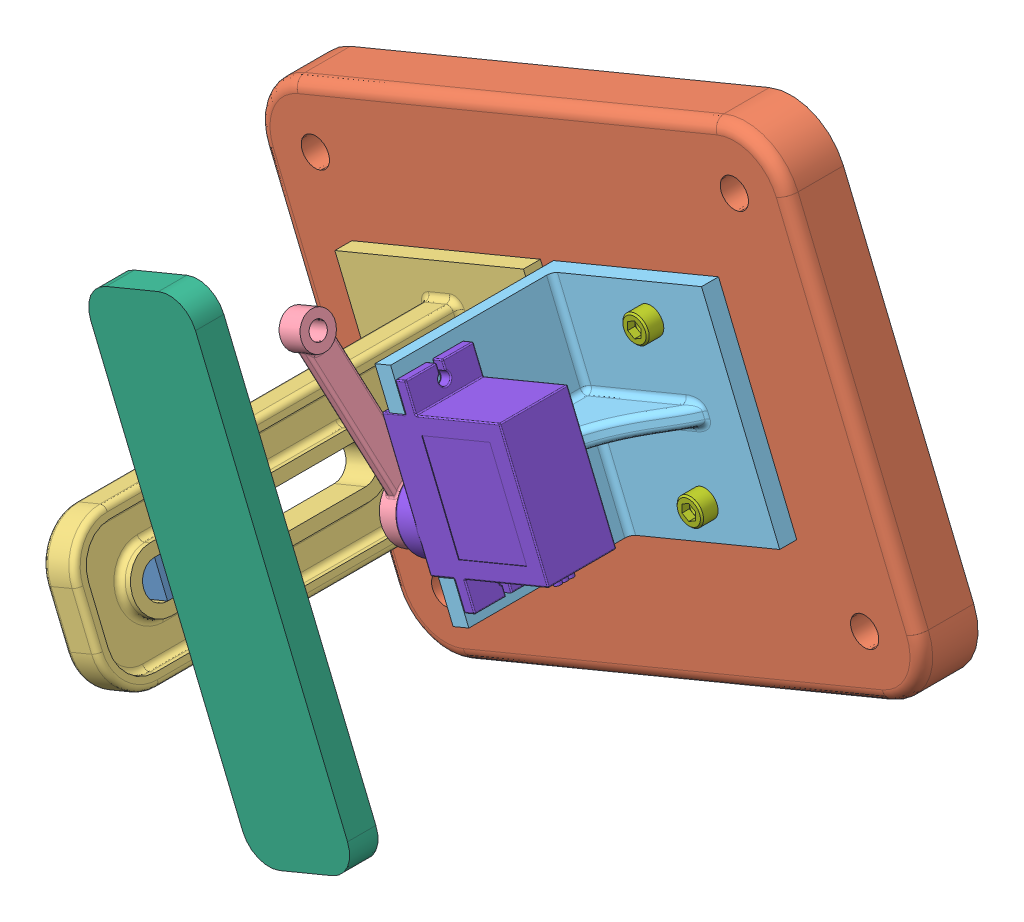
SolidWorks assembly Motion Study Assembly, configuration Default. Lengths in mm.
Overall size (123.02 112.2 83).
12 component instances, 8 part files, 33 mates.
Components (placement in the parent):
- Motion Study Clip-1: Motion Study Clip [Default] at (-120.8204 31.4961 70.2024) x (-0.383049 0.923728 0) z (0.923728 0.383049 0) size (10 7 8)
- Motion Study Base-1: Motion Study Base [Default] at (-97.7272 41.0724 3.7603) x (0.923728 0.383049 0) z (0 0 1) size (100 80 10)
- Motion Study Bracket-1: Motion Study Bracket [Default] at (-116.2018 33.4114 16.7603) x (-0.923728 -0.383049 0) z (0 0 -1) size (36 36 73)
- Motion Study Servo Arm-1: Motion Study Servo Arm [Default] at (-107.6727 46.7817 43.6818) x (0.36603 -0.882686 -0.294768) z (-0.923728 -0.383049 0) size (38 10 4)
- Motion Study Servo Mount-1: Motion Study Servo Mount [Default] at (-95.8797 41.8385 15.2603) x (0.923728 0.383049 0) z (0.383049 -0.923728 0) size (31.5 31.5 36)
- Motion Study Shelf-1: Motion Study Shelf [Default] at (-104.1933 38.391 72.7024) x (-0.383049 0.923728 0) z (0 0 -1) size (80 26 5)
- socket head cap screw_ai-13: socket head cap screw_ai [HX-SHCS 0.112-40x0.125x0.125-N] at (-84.0408 60.2799 19.6051) x (0 0 -1) z (1 0 0) size (6.02 4.65 4.65)
- socket head cap screw_ai-14: socket head cap screw_ai [HX-SHCS 0.112-40x0.125x0.125-N] at (-74.4645 37.1867 19.6051) x (0 0 -1) z (1 0 0) size (6.02 4.65 4.65)
- socket head cap screw_ai-15: socket head cap screw_ai [HX-SHCS 0.112-40x0.125x0.125-N] at (-106.9645 37.2419 19.6051) x (0 0 -1) z (1 0 0) size (6.02 4.65 4.65)
- socket head cap screw_ai-16: socket head cap screw_ai [HX-SHCS 0.112-40x0.125x0.125-N] at (-125.439 29.5809 19.6051) x (0 0 -1) z (1 0 0) size (6.02 4.65 4.65)
- socket head cap screw_ai-17: socket head cap screw_ai [HX-SHCS 0.112-40x0.125x0.125-N] at (-123.4482 30.4064 70.2024) x (0.923728 0.383049 0) z (0 0 1) size (6.02 4.65 4.65)
- Micro Servo SG92R 180-1: Micro Servo SG92R 180 [Valor predeterminado] at (-92.6467 43.1791 39.2603) x (-0.383049 0.923728 0) z (0 0 1) size (32 29 12)
Mates (geometry in assembly coordinates):
- Coincident9: coincident anti-aligned: plane of Motion Study Base-1 through (-97.7272 41.0724 13.7603) normal (0 0 1); plane of Motion Study Bracket-1 through (-116.2018 33.4114 13.7603) normal (0 0 -1)
- Concentric7: concentric aligned: cylinder of Motion Study Base-1 through (-106.9645 37.2419 3.7603) axis (0 0 1) radius 1.5; cylinder of Motion Study Bracket-1 through (-106.9645 37.2419 13.7603) axis (0 0 1) radius 1.5
- Concentric8: concentric aligned: cylinder of Motion Study Base-1 through (-125.439 29.5809 3.7603) axis (0 0 1) radius 1.5; cylinder of Motion Study Bracket-1 through (-125.439 29.5809 13.7603) axis (0 0 1) radius 1.5
- Coincident10: coincident anti-aligned: plane of Motion Study Base-1 through (-97.7272 41.0724 13.7603) normal (0 0 1); plane of Motion Study Servo Mount-1 through (-88.9849 25.2114 13.7603) normal (0 0 -1)
- Concentric10: concentric aligned: cylinder of Motion Study Base-1 through (-84.0408 60.2799 3.7603) axis (0 0 1) radius 1.5; cylinder of Motion Study Servo Mount-1 through (-84.0408 60.2799 6.7603) axis (0 0 1) radius 1.5
- Concentric11: concentric aligned: cylinder of Motion Study Base-1 through (-74.4645 37.1867 3.7603) axis (0 0 1) radius 1.5; cylinder of Motion Study Servo Mount-1 through (-74.4645 37.1867 6.7603) axis (0 0 1) radius 1.5
- Coincident11: coincident anti-aligned: plane of Motion Study Clip-1 through (-118.9729 32.2622 56.3994) normal (0.923728 0.383049 0); plane of Motion Study Bracket-1 through (-114.1848 20.7156 86.7603) normal (-0.923728 -0.383049 0)
- Coincident12: coincident anti-aligned: plane of Motion Study Clip-1 through (-112.2814 31.7893 58.8994) normal (0.383049 -0.923728 0); plane of Motion Study Bracket-1 through (-53.1628 56.3045 73.7603) normal (-0.383049 0.923728 0)
- Coincident14: coincident anti-aligned: plane of Motion Study Clip-1 through (-118.9729 32.2622 56.3994) normal (0.923728 0.383049 0); plane of Motion Study Shelf-1 through (-118.9729 32.2622 58.8994) normal (-0.923728 -0.383049 0)
- Concentric13: concentric aligned: cylinder of Motion Study Clip-1 through (-118.9729 32.2622 56.3994) axis (-0.923728 -0.383049 0) radius 1.425; cylinder of Motion Study Shelf-1 through (-115.278 33.7944 56.3994) axis (-0.923728 -0.383049 0) radius 2
- Coincident16: coincident anti-aligned: plane of Motion Study Clip-1 through (-114.5797 37.3317 53.8994) normal (0 0 1); plane of Motion Study Shelf-1 through (-104.1933 38.391 53.8994) normal (0 0 -1)
- Concentric14: concentric aligned: cylinder of Motion Study Servo Mount-1 through (-84.0408 60.2799 6.7603) axis (0 0 1) radius 1.5; cylinder of socket head cap screw_ai-13 through (-84.0408 60.2799 51.3551) axis (0 0 1) radius 2.3241
- Coincident17: coincident anti-aligned: plane of Motion Study Servo Mount-1 through (-88.9849 25.2114 16.7603) normal (0 0 1); plane of socket head cap screw_ai-13 through (-84.0408 62.604 16.7603) normal (0 0 -1)
- Concentric15: concentric aligned: cylinder of Motion Study Servo Mount-1 through (-74.4645 37.1867 6.7603) axis (0 0 1) radius 1.5; cylinder of socket head cap screw_ai-14 through (-74.4645 37.1867 51.3551) axis (0 0 1) radius 2.3241
- Coincident18: coincident anti-aligned: plane of Motion Study Servo Mount-1 through (-88.9849 25.2114 16.7603) normal (0 0 1); plane of socket head cap screw_ai-14 through (-74.4645 39.5108 16.7603) normal (0 0 -1)
- Concentric16: concentric aligned: cylinder of Motion Study Bracket-1 through (-106.9645 37.2419 13.7603) axis (0 0 1) radius 1.5; cylinder of socket head cap screw_ai-15 through (-106.9645 37.2419 51.3551) axis (0 0 1) radius 2.3241
- Coincident19: coincident anti-aligned: plane of Motion Study Bracket-1 through (-116.2018 33.4114 16.7603) normal (0 0 1); plane of socket head cap screw_ai-15 through (-106.9645 39.566 16.7603) normal (0 0 -1)
- Concentric17: concentric aligned: cylinder of Motion Study Bracket-1 through (-125.439 29.5809 13.7603) axis (0 0 1) radius 1.5; cylinder of socket head cap screw_ai-16 through (-125.439 29.5809 51.3551) axis (0 0 1) radius 2.3241
- Coincident20: coincident anti-aligned: plane of Motion Study Bracket-1 through (-116.2018 33.4114 16.7603) normal (0 0 1); plane of socket head cap screw_ai-16 through (-125.439 31.905 16.7603) normal (0 0 -1)
- Concentric18: concentric aligned: cylinder of Motion Study Clip-1 through (-118.9729 32.2622 56.3994) axis (-0.923728 -0.383049 0) radius 1.425; cylinder of socket head cap screw_ai-17 through (-152.7766 18.2446 56.3994) axis (-0.923728 -0.383049 0) radius 2.3241
- Coincident21: coincident anti-aligned: plane of Motion Study Clip-1 through (-120.8204 31.4961 56.3994) normal (-0.923728 -0.383049 0); plane of socket head cap screw_ai-17 through (-121.7106 33.643 56.3994) normal (0.923728 0.383049 0)
- Concentric25: concentric anti-aligned: cylinder of Motion Study Servo Arm-1 through (-17.6884 -0.5112 -4.1917) axis (-0.923728 -0.383049 0) radius 2.25; cylinder of Micro Servo SG92R 180-1 through (-23.6926 -3.001 -4.1917) axis (0.923728 0.383049 0) radius 2.25
- Coincident28: coincident anti-aligned: plane of Motion Study Servo Arm-1 through (-21.3833 -2.0434 -4.1917) normal (0.923728 0.383049 0); plane of Micro Servo SG92R 180-1 through (-21.3833 -2.0434 -4.1917) normal (-0.923728 -0.383049 0)
- Coincident29: coincident anti-aligned: plane of Motion Study Servo Mount-1 through (-8.6477 -10.565 -28.1917) normal (0.923728 0.383049 0); plane of Micro Servo SG92R 180-1 through (-20.7617 18.6479 -4.1917) normal (-0.923728 -0.383049 0)
- Concentric26: concentric aligned: cylinder of Motion Study Servo Mount-1 through (-29.9989 14.8174 -4.1917) axis (0.923728 0.383049 0) radius 1; cylinder of Micro Servo SG92R 180-1 through (-20.7617 18.6479 -4.1917) axis (0.923728 0.383049 0) radius 1
- Concentric27: concentric aligned: cylinder of Motion Study Servo Mount-1 through (-19.5608 -10.3542 -4.1917) axis (0.923728 0.383049 0) radius 1; cylinder of Micro Servo SG92R 180-1 through (-10.3236 -6.5237 -4.1917) axis (0.923728 0.383049 0) radius 1
- Tangent5: tangent: circle of Motion Study Servo Arm-1; plane of Motion Study Shelf-1 through (-25.2418 2.0401 -28.9035) normal (0 0 -1)
- Tangent6: tangent anti-aligned: cylinder of Motion Study Servo Arm-1 through (-29.48 7.0394 -31.9035) axis (0.923728 0.383049 0) radius 3; plane of Motion Study Shelf-1 through (-25.2418 2.0401 -28.9035) normal (0 0 -1)
- Coincident30: coincident anti-aligned: plane of Motion Study Servo Mount-1 through (-87.5993 25.7859 15.2603) normal (0.923728 0.383049 0); plane of Micro Servo SG92R 180-1 through (-99.7132 54.9988 39.2603) normal (-0.923728 -0.383049 0)
- Concentric28: concentric aligned: cylinder of Motion Study Servo Mount-1 through (-98.5124 25.9967 39.2603) axis (0.923728 0.383049 0) radius 1; cylinder of Micro Servo SG92R 180-1 through (-89.2751 29.8272 39.2603) axis (0.923728 0.383049 0) radius 1
- Concentric29: concentric aligned: cylinder of Motion Study Servo Mount-1 through (-108.9505 51.1683 39.2603) axis (0.923728 0.383049 0) radius 1; cylinder of Micro Servo SG92R 180-1 through (-99.7132 54.9988 39.2603) axis (0.923728 0.383049 0) radius 1
- Concentric30: concentric anti-aligned: cylinder of Motion Study Servo Arm-1 through (-96.6399 35.8397 39.2603) axis (-0.923728 -0.383049 0) radius 2.25; cylinder of Micro Servo SG92R 180-1 through (-102.6442 33.3499 39.2603) axis (0.923728 0.383049 0) radius 2.25
- Coincident31: coincident anti-aligned: plane of Motion Study Servo Arm-1 through (-100.3348 34.3075 39.2603) normal (0.923728 0.383049 0); plane of Micro Servo SG92R 180-1 through (-100.3348 34.3075 39.2603) normal (-0.923728 -0.383049 0)
